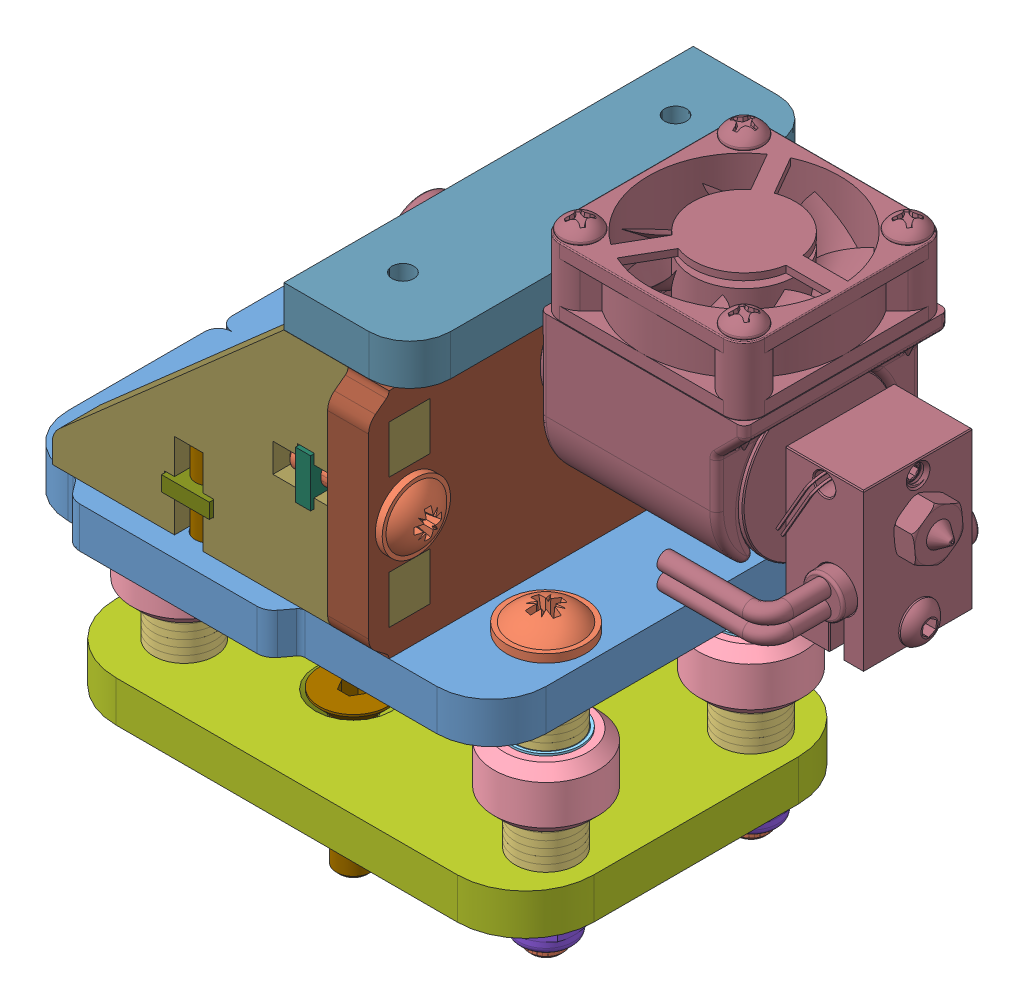
SolidWorks assembly carriage_axis_x, configuration По умолчанию. Lengths in mm.
Overall size (118.69 102.68 87.12).
97 component instances, 16 part files, 168 mates.
Components (placement in the parent):
- carriage_axis_x_plywood-3: carriage_axis_x_plywood [По умолчанию] at origin size (101.86 6 70.03)
- DIN967-1: DIN967 [М5х40] at (-25 9.55 -15) x (0 -1 0) z (0 0 1) size (43.47 34 34.42)
- DIN967-2: DIN967 [М5х40] at (-25 9.55 15) x (0 -1 0) z (0 0 1) size (43.47 34 34.42)
- DIN967-3: DIN967 [М5х40] at (28 9.55 -15) x (0 -1 0) z (0 0 1) size (43.47 34 34.42)
- DIN967-4: DIN967 [М5х40] at (28 9.55 15) x (0 -1 0) z (0.973575 0 0.228367) size (43.47 34 34.42)
- din433_m5-1: din433_m5 [По умолчанию] at (28 0 15) x (1 0 0) z (0 -1 0) size (9 9 1)
- din433_m5-2: din433_m5 [По умолчанию] at (28 -2 15) x (-0.882011 0 -0.471229) z (0 1 0) size (9 9 1)
- din433_m5-3: din433_m5 [По умолчанию] at (28 -3 15) x (-0.882011 0 -0.471229) z (0 1 0) size (9 9 1)
- din433_m5-4: din433_m5 [По умолчанию] at (28 -4 15) x (-0.882011 0 -0.471229) z (0 1 0) size (9 9 1)
- din433_m5-5: din433_m5 [По умолчанию] at (28 -5 15) x (-0.986157 0 -0.165812) z (0 1 0) size (9 9 1)
- din433_m5-6: din433_m5 [По умолчанию] at (28 -3 -15) x (-0.882011 0 -0.471229) z (0 1 0) size (9 9 1)
- din433_m5-7: din433_m5 [По умолчанию] at (28 -2 -15) x (-0.882011 0 -0.471229) z (0 1 0) size (9 9 1)
- din433_m5-8: din433_m5 [По умолчанию] at (28 -1 -15) x (-0.706556 0 -0.707657) z (0 1 0) size (9 9 1)
- din433_m5-9: din433_m5 [По умолчанию] at (28 -4 -15) x (-0.882011 0 -0.471229) z (0 1 0) size (9 9 1)
- din433_m5-10: din433_m5 [По умолчанию] at (28 -5 -15) x (0.996128 0 0.087912) z (0 -1 0) size (9 9 1)
- din433_m5-11: din433_m5 [По умолчанию] at (28 -5 -15) x (-0.882011 0 -0.471229) z (0 1 0) size (9 9 1)
- din433_m5-12: din433_m5 [По умолчанию] at (-25 -3 15) x (-0.955012 0 -0.296566) z (0 1 0) size (9 9 1)
- din433_m5-13: din433_m5 [По умолчанию] at (-25 -4 15) x (-0.955012 0 -0.296566) z (0 1 0) size (9 9 1)
- din433_m5-14: din433_m5 [По умолчанию] at (-25 -5 15) x (-0.827257 0 -0.561823) z (0 1 0) size (9 9 1)
- din433_m5-15: din433_m5 [По умолчанию] at (-25 -2 15) x (-0.955012 0 -0.296566) z (0 1 0) size (9 9 1)
- din433_m5-16: din433_m5 [По умолчанию] at (-25 0 15) x (0.982082 0 -0.188455) z (0 -1 0) size (9 9 1)
- din433_m5-17: din433_m5 [По умолчанию] at (-25 -2 -15) x (-0.996489 0 -0.083718) z (0 1 0) size (9 9 1)
- din433_m5-18: din433_m5 [По умолчанию] at (-25 -3 -15) x (-0.996489 0 -0.083718) z (0 1 0) size (9 9 1)
- din433_m5-19: din433_m5 [По умолчанию] at (-25 -4 -15) x (-0.928921 0 -0.370279) z (0 1 0) size (9 9 1)
- din433_m5-20: din433_m5 [По умолчанию] at (-25 -1 -15) x (-0.996489 0 -0.083718) z (0 1 0) size (9 9 1)
- din433_m5-28: din433_m5 [По умолчанию] at (-25 -5 -15) x (0.980186 0 0.198081) z (0 -1 0) size (9 9 1)
- din433_m5-29: din433_m5 [По умолчанию] at (-25 -4 -15) x (0.980186 0 0.198081) z (0 -1 0) size (9 9 1)
- din433_m5-27: din433_m5 [По умолчанию] at (28 -5 15) x (0.91627 0 0.40056) z (0 -1 0) size (9 9 1)
- din433_m5-21: din433_m5 [По умолчанию] at (-25 -6 15) x (-0.552382 0 -0.833591) z (0 1 0) size (9 9 1)
- Delrin Mini V Wheel Kit-1: Delrin Mini V Wheel Kit [По умолчанию] at (-25 -10.7 15) x (0 1 0) z (0 0 1) size (9.4 15.23 15.23)
  - Delrin Mini V Wheel-1: Delrin Mini V Wheel [Default] at origin size (8.8 15.23 15.23)
  - Mini Ball Bearing 105zz 5x10x4-1: Mini Ball Bearing 105zz 5x10x4 [Default] at (2.6 0 0) size (4.2 10 10)
  - Mini Ball Bearing 105zz 5x10x4-2: Mini Ball Bearing 105zz 5x10x4 [Default] at (-2.6 0 0) size (4.2 10 10)
  - Mini V Wheel Precision Shim-2: Mini V Wheel Precision Shim [По умолчанию] at (-0.5 0 0) size (1 8 8)
- din433_m5-30: din433_m5 [По умолчанию] at (-25 -19.4 15) x (0.999952 0 0.009811) z (0 -1 0) size (9 9 1)
- din433_m5-31: din433_m5 [По умолчанию] at (-25 -20.4 15) x (0.999952 0 0.009811) z (0 -1 0) size (9 9 1)
- din433_m5-32: din433_m5 [По умолчанию] at (-25 -16.4 15) x (-0.994411 0 0.105575) z (0 1 0) size (9 9 1)
- din433_m5-33: din433_m5 [По умолчанию] at (-25 -19.4 15) x (-0.982057 0 -0.188585) z (0 1 0) size (9 9 1)
- din433_m5-34: din433_m5 [По умолчанию] at (-25 -18.4 15) x (-0.994411 0 0.105575) z (0 1 0) size (9 9 1)
- din433_m5-35: din433_m5 [По умолчанию] at (-25 -17.4 15) x (-0.994411 0 0.105575) z (0 1 0) size (9 9 1)
- Delrin Mini V Wheel Kit-2: Delrin Mini V Wheel Kit [По умолчанию] at (-25 -10.7 -15) x (0 -1 0) z (0.990454 0 -0.137844) size (9.4 15.23 15.23)
  - Delrin Mini V Wheel-1: Delrin Mini V Wheel [Default] at origin size (8.8 15.23 15.23)
  - Mini Ball Bearing 105zz 5x10x4-1: Mini Ball Bearing 105zz 5x10x4 [Default] at (2.6 0 0) size (4.2 10 10)
  - Mini Ball Bearing 105zz 5x10x4-2: Mini Ball Bearing 105zz 5x10x4 [Default] at (-2.6 0 0) size (4.2 10 10)
  - Mini V Wheel Precision Shim-2: Mini V Wheel Precision Shim [По умолчанию] at (-0.5 0 0) size (1 8 8)
- din433_m5-42: din433_m5 [По умолчанию] at (-25 -20.4 -15) x (0.983884 0 -0.17881) z (0 -1 0) size (9 9 1)
- din433_m5-43: din433_m5 [По умолчанию] at (-25 -16.4 -15) x (-0.956697 0 0.291085) z (0 1 0) size (9 9 1)
- din433_m5-44: din433_m5 [По умолчанию] at (-25 -19.4 -15) x (-1 0 -0.000132) z (0 1 0) size (9 9 1)
- din433_m5-45: din433_m5 [По умолчанию] at (-25 -18.4 -15) x (-0.956697 0 0.291085) z (0 1 0) size (9 9 1)
- din433_m5-46: din433_m5 [По умолчанию] at (-25 -17.4 -15) x (-0.956697 0 0.291085) z (0 1 0) size (9 9 1)
- din433_m5-47: din433_m5 [По умолчанию] at (-25 -19.4 -15) x (0.983884 0 -0.17881) z (0 -1 0) size (9 9 1)
- Delrin Mini V Wheel Kit-3: Delrin Mini V Wheel Kit [По умолчанию] at (28 -10.7 -15) x (0 1 0) z (0 0 1) size (9.4 15.23 15.23)
  - Delrin Mini V Wheel-1: Delrin Mini V Wheel [Default] at origin size (8.8 15.23 15.23)
  - Mini Ball Bearing 105zz 5x10x4-1: Mini Ball Bearing 105zz 5x10x4 [Default] at (2.6 0 0) size (4.2 10 10)
  - Mini Ball Bearing 105zz 5x10x4-2: Mini Ball Bearing 105zz 5x10x4 [Default] at (-2.6 0 0) size (4.2 10 10)
  - Mini V Wheel Precision Shim-2: Mini V Wheel Precision Shim [По умолчанию] at (-0.5 0 0) size (1 8 8)
- Delrin Mini V Wheel Kit-4: Delrin Mini V Wheel Kit [По умолчанию] at (28 -10.7 15) x (0 -1 0) z (-0.546944 0 0.837169) size (9.4 15.23 15.23)
  - Delrin Mini V Wheel-1: Delrin Mini V Wheel [Default] at origin size (8.8 15.23 15.23)
  - Mini Ball Bearing 105zz 5x10x4-1: Mini Ball Bearing 105zz 5x10x4 [Default] at (2.6 0 0) size (4.2 10 10)
  - Mini Ball Bearing 105zz 5x10x4-2: Mini Ball Bearing 105zz 5x10x4 [Default] at (-2.6 0 0) size (4.2 10 10)
  - Mini V Wheel Precision Shim-2: Mini V Wheel Precision Shim [По умолчанию] at (-0.5 0 0) size (1 8 8)
- din433_m5-54: din433_m5 [По умолчанию] at (28 -16.4 15) x (-0.124351 0 0.992238) z (0 1 0) size (9 9 1)
- din433_m5-55: din433_m5 [По умолчанию] at (28 -19.4 15) x (-0.982107 0 0.188325) z (0 1 0) size (9 9 1)
- din433_m5-56: din433_m5 [По умолчанию] at (28 -18.4 15) x (-0.884699 0 0.466164) z (0 1 0) size (9 9 1)
- din433_m5-57: din433_m5 [По умолчанию] at (28 -17.4 15) x (-0.884699 0 0.466164) z (0 1 0) size (9 9 1)
- din433_m5-58: din433_m5 [По умолчанию] at (28 -19.4 15) x (0.932557 0 -0.361024) z (0 -1 0) size (9 9 1)
- din433_m5-59: din433_m5 [По умолчанию] at (28 -20.4 15) x (0.932557 0 -0.361024) z (0 -1 0) size (9 9 1)
- din433_m5-132: din433_m5 [По умолчанию] at (28 -18.4 -15) x (-0.884699 0 0.466164) z (0 1 0) size (9 9 1)
- din433_m5-133: din433_m5 [По умолчанию] at (28 -20.4 -15) x (0.932557 0 -0.361024) z (0 -1 0) size (9 9 1)
- din433_m5-134: din433_m5 [По умолчанию] at (28 -19.4 -15) x (0.932557 0 -0.361024) z (0 -1 0) size (9 9 1)
- din433_m5-135: din433_m5 [По умолчанию] at (28 -17.4 -15) x (-0.884699 0 0.466164) z (0 1 0) size (9 9 1)
- din433_m5-136: din433_m5 [По умолчанию] at (28 -19.4 -15) x (-0.982107 0 0.188325) z (0 1 0) size (9 9 1)
- din433_m5-137: din433_m5 [По умолчанию] at (28 -16.4 -15) x (0.998156 0 0.060708) z (0 1 0) size (9 9 1)
- carriage_axis_x_plywood_bottom-2: carriage_axis_x_plywood_bottom [По умолчанию] at (0 -27.4 0) size (70 6 50)
- DIN 985-1: DIN 985 [Verzle DIN 985 - M5] at (-25 -27.4 -15) x (0 1 0) z (1 0 0) size (5 9.24 8)
- DIN 985-2: DIN 985 [Verzle DIN 985 - M5] at (-25 -27.4 15) x (0 1 0) z (1 0 0) size (5 9.24 8)
- DIN 985-3: DIN 985 [Verzle DIN 985 - M5] at (28 -27.4 -15) x (0 1 0) z (1 0 0) size (5 9.24 8)
- DIN 985-4: DIN 985 [Verzle DIN 985 - M5] at (28 -27.4 15) x (0 1 0) z (1 0 0) size (5 9.24 8)
- DIN 7991-1: DIN 7991 [ISO 7991 M05 x  20] at (-6.1594 -21.1 9.0403) x (0 -1 0) z (0 0 1) size (22.8 40 22.08)
- DIN 7991-2: DIN 7991 [ISO 7991 M05 x  20] at (-6.1594 -21.7 -8.1926) x (0 -1 0) z (0 0 1) size (22.8 40 22.08)
- din433_m5-138: din433_m5 [По умолчанию] at (-6.1594 -28.4 -8.1926) x (-0.996489 0 -0.083718) z (0 1 0) size (9 9 1)
- din433_m5-139: din433_m5 [По умолчанию] at (-6.1594 -28.4 9.0403) x (-0.996489 0 -0.083718) z (0 1 0) size (9 9 1)
- DIN 439-1: DIN 439 [По умолчанию] at (-6.1594 -31.1 -8.1926) size (9.08 2.7 8)
- DIN 439-2: DIN 439 [По умолчанию] at (-6.1594 -31.1 9.0403) size (9.08 2.7 8)
- carriage_x_console-1: carriage_x_console [По умолчанию] at (20 37.0784 4.0204) x (0 0 -1) z (-1 0 0) size (66 34 6)
- carriage_x_console_rectangel-1: carriage_x_console_rectangel [По умолчанию] at (-30.8109 -0.0784 24) x (-1 0 0) z (0 0 -1) size (62 46 6)
- carriage_x_console_rectangel-2: carriage_x_console_rectangel [По умолчанию] at (-30.8109 -0.0784 -30) x (-1 0 0) z (0 0 -1) size (62 46 6)
- Kit Extrusora - Hotend E3D-V6_175-300-1: Kit Extrusora - Hotend E3D-V6_175-300 [По умолчанию] at (72.5 32 0) x (0 0 1) z (0 -1 0) size (34.25 77.7 41.62)
- Деталь4^carriage_axis_x-1: Деталь4^carriage_axis_x [По умолчанию] at (20 40 4.0204) x (0 0 1) z (0 1 0) size (59.93 19.62 6) (virtual)
- DIN967-5: DIN967 [M4х16] at (23.05 23 27) x (-1 0 0) z (0 0 1) size (18.96 34 34.42)
- din 562 m4-1: din 562 m4 [По умолчанию] at (9 23.0002 26.9982) x (0 -1 0) z (-1 0 0) size (7 7 2.2)
- DIN967-6: DIN967 [M4х16] at (23.05 23 -27) x (-1 0 0) z (0 0 -1) size (18.96 34 34.42)
- din 562 m4-2: din 562 m4 [По умолчанию] at (9 22.9998 -26.9982) x (0 1 0) z (-1 0 0) size (7 7 2.2)
- DIN 7991-3: DIN 7991 [ISO 7991 M04 x  16] at (-9.3228 0 -27) x (0 1 0) z (0 0 -1) size (18.3 40 22.08)
- din 562 m4din-1: din 562 m4din [По умолчанию] at (-9.3228 11 -27) x (1 0 0) z (0 1 0) size (7 7 2.2)
- DIN 7991-4: DIN 7991 [ISO 7991 M04 x  16] at (-9.3228 0 27) x (0 1 0) z (0 0 1) size (18.3 40 22.08)
- din 562 m4din-2: din 562 m4din [По умолчанию] at (-9.3228 11 27) x (-1 0 0) z (0 1 0) size (7 7 2.2)
Mates (geometry in assembly coordinates):
- Концентричный11: concentric anti-aligned: cylinder of carriage_axis_x_plywood-3 through (-25 6 -15) axis (0 -1 0) radius 2.55; cylinder of DIN967-1 through (-25 15.9 -15) axis (0 1 0) radius 5.75
- Совпадение11: coincident anti-aligned: plane of carriage_axis_x_plywood-3 through (27 6 -22) normal (0 1 0); plane of DIN967-1 through (-22.5 6 -15) normal (0 -1 0)
- Концентричный21: concentric anti-aligned: cylinder of carriage_axis_x_plywood-3 through (-25 6 15) axis (0 -1 0) radius 2.55; cylinder of DIN967-2 through (-25 15.9 15) axis (0 1 0) radius 5.75
- Совпадение21: coincident anti-aligned: plane of carriage_axis_x_plywood-3 through (27 6 -22) normal (0 1 0); plane of DIN967-2 through (-22.5 6 15) normal (0 -1 0)
- Концентричный31: concentric anti-aligned: cylinder of DIN967-3 through (28 15.9 -15) axis (0 1 0) radius 5.75; circle of carriage_axis_y_plywood_left-1
- Совпадение31: coincident anti-aligned: plane of carriage_axis_x_plywood-3 through (27 6 -22) normal (0 1 0); plane of DIN967-3 through (30.5 6 -15) normal (0 -1 0)
- Совпадение41: coincident anti-aligned: plane of carriage_axis_x_plywood-3 through (27 6 -22) normal (0 1 0); plane of DIN967-4 through (28.5709 6 12.5661) normal (0 -1 0)
- Концентричный5: concentric anti-aligned: cylinder of carriage_axis_x_plywood-3 through (28 6 15) axis (0 -1 0) radius 2.55; cylinder of DIN967-4 through (28 15.9 15) axis (0 1 0) radius 2.5
- Совпадение5: coincident anti-aligned: plane of carriage_axis_x_plywood-3 through (27 0 -22) normal (0 -1 0); plane of din433_m5-1 through (28 0 15) normal (0 1 0)
- Концентричный6: concentric anti-aligned: cylinder of DIN967-4 through (28 15.9 15) axis (0 1 0) radius 2.5; circle of din433_m5-1
- Концентричный7: concentric aligned: cylinder of DIN967-4 through (28 15.9 15) axis (0 1 0) radius 2.5; circle of din433_m5-2
- Совпадение7: coincident anti-aligned: plane of din433_m5-1 through (28 -1 15) normal (0 -1 0); plane of din433_m5-2 through (28 -1 15) normal (0 1 0)
- Совпадение10: coincident anti-aligned: plane of din433_m5-3 through (28 -3 15) normal (0 -1 0); plane of din433_m5-4 through (28 -3 15) normal (0 1 0)
- Совпадение11: coincident aligned: circle of din433_m5-3; circle of din433_m5-4
- Совпадение12: coincident anti-aligned: plane of din433_m5-4 through (28 -4 15) normal (0 -1 0); plane of din433_m5-5 through (28 -4 15) normal (0 1 0)
- Совпадение13: coincident aligned: circle of din433_m5-4; circle of din433_m5-5
- Совпадение14: coincident anti-aligned: plane of din433_m5-2 through (28 -2 15) normal (0 -1 0); plane of din433_m5-3 through (28 -2 15) normal (0 1 0)
- Совпадение15: coincident aligned: circle of din433_m5-2; circle of din433_m5-3
- Совпадение16: coincident anti-aligned: plane of carriage_axis_x_plywood-3 through (27 0 -22) normal (0 -1 0); plane of din433_m5-8 through (28 0 -15) normal (0 1 0)
- Концентричный8: concentric aligned: cylinder of DIN967-3 through (28 15.9 -15) axis (0 1 0) radius 2.5; circle of din433_m5-8
- Совпадение17: coincident anti-aligned: plane of din433_m5-7 through (28 -1 -15) normal (0 1 0); plane of din433_m5-8 through (28 -1 -15) normal (0 -1 0)
- Совпадение18: coincident aligned: circle of din433_m5-7; circle of din433_m5-8
- Совпадение19: coincident anti-aligned: plane of din433_m5-6 through (28 -2 -15) normal (0 1 0); plane of din433_m5-7 through (28 -2 -15) normal (0 -1 0)
- Концентричный9: concentric aligned: cylinder of DIN967-3 through (28 15.9 -15) axis (0 1 0) radius 2.5; circle of din433_m5-6
- Совпадение20: coincident anti-aligned: plane of din433_m5-6 through (28 -3 -15) normal (0 -1 0); plane of din433_m5-9 through (28 -3 -15) normal (0 1 0)
- Концентричный10: concentric aligned: cylinder of DIN967-3 through (28 15.9 -15) axis (0 1 0) radius 2.5; circle of din433_m5-9
- Совпадение22: coincident anti-aligned: plane of din433_m5-9 through (28 -4 -15) normal (0 -1 0); plane of din433_m5-11 through (28 -4 -15) normal (0 1 0)
- Концентричный11: concentric aligned: cylinder of DIN967-3 through (28 15.9 -15) axis (0 1 0) radius 2.5; circle of din433_m5-11
- Совпадение23: coincident anti-aligned: plane of din433_m5-10 through (28 -5 -15) normal (0 1 0); plane of din433_m5-11 through (28 -5 -15) normal (0 -1 0)
- Концентричный13: concentric anti-aligned: cylinder of DIN967-3 through (28 15.9 -15) axis (0 1 0) radius 2.5; circle of din433_m5-10
- Совпадение24: coincident anti-aligned: plane of din433_m5-15 through (-25 -1 15) normal (0 1 0); plane of din433_m5-16 through (-25 -1 15) normal (0 -1 0)
- Совпадение25: coincident anti-aligned: plane of din433_m5-12 through (-25 -3 15) normal (0 -1 0); plane of din433_m5-13 through (-25 -3 15) normal (0 1 0)
- Совпадение26: coincident aligned: circle of din433_m5-12; circle of din433_m5-13
- Совпадение27: coincident anti-aligned: plane of din433_m5-13 through (-25 -4 15) normal (0 -1 0); plane of din433_m5-14 through (-25 -4 15) normal (0 1 0)
- Совпадение28: coincident aligned: circle of din433_m5-13; circle of din433_m5-14
- Совпадение29: coincident anti-aligned: plane of din433_m5-12 through (-25 -2 15) normal (0 1 0); plane of din433_m5-15 through (-25 -2 15) normal (0 -1 0)
- Совпадение30: coincident aligned: circle of din433_m5-12; circle of din433_m5-15
- Совпадение33: coincident anti-aligned: plane of din433_m5-17 through (-25 -2 -15) normal (0 -1 0); plane of din433_m5-18 through (-25 -2 -15) normal (0 1 0)
- Совпадение34: coincident aligned: circle of din433_m5-17; circle of din433_m5-18
- Совпадение35: coincident anti-aligned: plane of din433_m5-18 through (-25 -3 -15) normal (0 -1 0); plane of din433_m5-19 through (-25 -3 -15) normal (0 1 0)
- Совпадение36: coincident aligned: circle of din433_m5-18; circle of din433_m5-19
- Совпадение37: coincident anti-aligned: plane of din433_m5-17 through (-25 -1 -15) normal (0 1 0); plane of din433_m5-20 through (-25 -1 -15) normal (0 -1 0)
- Совпадение38: coincident aligned: circle of din433_m5-17; circle of din433_m5-20
- Концентричный15: concentric aligned: cylinder of DIN967-2 through (-25 15.9 15) axis (0 1 0) radius 2.5; circle of din433_m5-14
- Концентричный16: concentric anti-aligned: cylinder of DIN967-2 through (-25 15.9 15) axis (0 1 0) radius 2.5; circle of din433_m5-16
- Совпадение54: coincident anti-aligned: plane of din433_m5-14 through (-25 -5 15) normal (0 -1 0); plane of din433_m5-21 through (-25 -5 15) normal (0 1 0)
- Концентричный17: concentric aligned: cylinder of DIN967-2 through (-25 15.9 15) axis (0 1 0) radius 2.5; circle of din433_m5-21
- Совпадение55: coincident anti-aligned: plane of din433_m5-5 through (28 -5 15) normal (0 -1 0); plane of din433_m5-27 through (28 -5 15) normal (0 1 0)
- Концентричный18: concentric anti-aligned: cylinder of DIN967-4 through (28 15.9 15) axis (0 1 0) radius 2.5; circle of din433_m5-27
- Концентричный19: concentric aligned: cylinder of DIN967-1 through (-25 15.9 -15) axis (0 1 0) radius 2.5; circle of din433_m5-20
- Совпадение56: coincident anti-aligned: plane of din433_m5-19 through (-25 -4 -15) normal (0 -1 0); plane of din433_m5-29 through (-25 -4 -15) normal (0 1 0)
- Концентричный20: concentric anti-aligned: cylinder of DIN967-1 through (-25 15.9 -15) axis (0 1 0) radius 2.5; circle of din433_m5-29
- Совпадение57: coincident anti-aligned: plane of din433_m5-28 through (-25 -5 -15) normal (0 1 0); plane of din433_m5-29 through (-25 -5 -15) normal (0 -1 0)
- Концентричный21: concentric anti-aligned: cylinder of DIN967-1 through (-25 15.9 -15) axis (0 1 0) radius 2.5; circle of din433_m5-28
- Совпадение58: coincident anti-aligned: plane of carriage_axis_x_plywood-3 through (27 0 -22) normal (0 -1 0); plane of din433_m5-20 through (-25 0 -15) normal (0 1 0)
- Совпадение59: coincident anti-aligned: plane of din433_m5-21 through (-25 -6 15) normal (0 -1 0); plane of Delrin Mini V Wheel Kit-1/Mini Ball Bearing 105zz 5x10x4-1 through (-27.5 -6 15) normal (0 1 0)
- Совпадение60: coincident aligned: cylinder of DIN967-2 through (-25 15.9 15) axis (0 1 0) radius 2.5; circle of Delrin Mini V Wheel Kit-1/Mini Ball Bearing 105zz 5x10x4-2
- Совпадение61: coincident anti-aligned: plane of din433_m5-34 through (-25 -17.4 15) normal (0 1 0); plane of din433_m5-35 through (-25 -17.4 15) normal (0 -1 0)
- Совпадение62: coincident aligned: circle of din433_m5-34; circle of din433_m5-35
- Совпадение63: coincident anti-aligned: plane of din433_m5-33 through (-25 -18.4 15) normal (0 1 0); plane of din433_m5-34 through (-25 -18.4 15) normal (0 -1 0)
- Совпадение64: coincident aligned: circle of din433_m5-33; circle of din433_m5-34
- Совпадение65: coincident anti-aligned: plane of din433_m5-32 through (-25 -16.4 15) normal (0 -1 0); plane of din433_m5-35 through (-25 -16.4 15) normal (0 1 0)
- Совпадение67: coincident anti-aligned: plane of din433_m5-30 through (-25 -19.4 15) normal (0 1 0); plane of din433_m5-33 through (-25 -19.4 15) normal (0 -1 0)
- Совпадение68: coincident anti-aligned: plane of din433_m5-30 through (-25 -20.4 15) normal (0 -1 0); plane of din433_m5-31 through (-25 -20.4 15) normal (0 1 0)
- Совпадение80: coincident anti-aligned: plane of Delrin Mini V Wheel Kit-1/Mini Ball Bearing 105zz 5x10x4-2 through (-27.5 -15.4 15) normal (0 -1 0); plane of din433_m5-32 through (-25 -15.4 15) normal (0 1 0)
- Концентричный22: concentric aligned: cylinder of DIN967-2 through (-25 15.9 15) axis (0 1 0) radius 2.5; circle of din433_m5-32
- Концентричный23: concentric aligned: cylinder of DIN967-2 through (-25 15.9 15) axis (0 1 0) radius 2.5; circle of din433_m5-35
- Концентричный24: concentric anti-aligned: cylinder of DIN967-2 through (-25 15.9 15) axis (0 1 0) radius 2.5; circle of din433_m5-30
- Концентричный25: concentric aligned: cylinder of DIN967-2 through (-25 15.9 15) axis (0 1 0) radius 2.5; cylinder of din433_m5-31 through (-25 -21.4 15) axis (0 1 0) radius 4.5
- Совпадение81: coincident anti-aligned: plane of din433_m5-28 through (-25 -6 -15) normal (0 -1 0); plane of Delrin Mini V Wheel Kit-2/Mini Ball Bearing 105zz 5x10x4-2 through (-25.3446 -6 -17.4761) normal (0 1 0)
- Совпадение82: coincident anti-aligned: cylinder of DIN967-1 through (-25 15.9 -15) axis (0 1 0) radius 2.5; circle of Delrin Mini V Wheel Kit-2/Mini Ball Bearing 105zz 5x10x4-1
- Совпадение83: coincident anti-aligned: plane of din433_m5-45 through (-25 -17.4 -15) normal (0 1 0); plane of din433_m5-46 through (-25 -17.4 -15) normal (0 -1 0)
- Совпадение84: coincident aligned: circle of din433_m5-45; circle of din433_m5-46
- Совпадение85: coincident anti-aligned: plane of din433_m5-44 through (-25 -18.4 -15) normal (0 1 0); plane of din433_m5-45 through (-25 -18.4 -15) normal (0 -1 0)
- Совпадение86: coincident aligned: circle of din433_m5-44; circle of din433_m5-45
- Совпадение87: coincident anti-aligned: plane of din433_m5-43 through (-25 -16.4 -15) normal (0 -1 0); plane of din433_m5-46 through (-25 -16.4 -15) normal (0 1 0)
- Совпадение88: coincident anti-aligned: plane of din433_m5-44 through (-25 -19.4 -15) normal (0 -1 0); plane of din433_m5-47 through (-25 -19.4 -15) normal (0 1 0)
- Совпадение89: coincident anti-aligned: plane of din433_m5-42 through (-25 -20.4 -15) normal (0 1 0); plane of din433_m5-47 through (-25 -20.4 -15) normal (0 -1 0)
- Совпадение99: coincident anti-aligned: plane of carriage_axis_x_plywood-3 through (27 0 -22) normal (0 -1 0); plane of din433_m5-16 through (-25 0 15) normal (0 1 0)
- Совпадение100: coincident anti-aligned: plane of Delrin Mini V Wheel Kit-2/Mini Ball Bearing 105zz 5x10x4-1 through (-25.3446 -15.4 -17.4761) normal (0 -1 0); plane of din433_m5-43 through (-25 -15.4 -15) normal (0 1 0)
- Концентричный26: concentric anti-aligned: circle of din433_m5-42; circle of din433_m5-43
- Концентричный27: concentric anti-aligned: circle of din433_m5-43; circle of din433_m5-47
- Концентричный28: concentric anti-aligned: circle of din433_m5-42; circle of din433_m5-44
- Концентричный29: concentric aligned: circle of Delrin Mini V Wheel Kit-2/Mini Ball Bearing 105zz 5x10x4-1; cylinder of din433_m5-43 through (-25 -15.4 -15) axis (0 -1 0) radius 4.5
- Совпадение104: coincident anti-aligned: plane of din433_m5-10 through (28 -6 -15) normal (0 -1 0); plane of Delrin Mini V Wheel Kit-3/Mini Ball Bearing 105zz 5x10x4-1 through (25.5 -6 -15) normal (0 1 0)
- Совпадение105: coincident aligned: cylinder of DIN967-3 through (28 15.9 -15) axis (0 1 0) radius 2.5; circle of Delrin Mini V Wheel Kit-3/Mini Ball Bearing 105zz 5x10x4-2
- Совпадение106: coincident anti-aligned: plane of din433_m5-27 through (28 -6 15) normal (0 -1 0); plane of Delrin Mini V Wheel Kit-4/Mini Ball Bearing 105zz 5x10x4-2 through (30.0929 -6 16.3674) normal (0 1 0)
- Концентричный30: concentric anti-aligned: cylinder of DIN967-4 through (28 15.9 15) axis (0 1 0) radius 2.5; cylinder of Delrin Mini V Wheel Kit-4/Mini Ball Bearing 105zz 5x10x4-1 through (28 -13.3 15) axis (0 -1 0) radius 2.5
- Совпадение107: coincident anti-aligned: plane of din433_m5-56 through (28 -17.4 15) normal (0 1 0); plane of din433_m5-57 through (28 -17.4 15) normal (0 -1 0)
- Совпадение108: coincident aligned: circle of din433_m5-56; circle of din433_m5-57
- Совпадение109: coincident anti-aligned: plane of din433_m5-55 through (28 -18.4 15) normal (0 1 0); plane of din433_m5-56 through (28 -18.4 15) normal (0 -1 0)
- Совпадение110: coincident aligned: circle of din433_m5-55; circle of din433_m5-56
- Совпадение111: coincident anti-aligned: plane of din433_m5-54 through (28 -16.4 15) normal (0 -1 0); plane of din433_m5-57 through (28 -16.4 15) normal (0 1 0)
- Совпадение112: coincident anti-aligned: plane of din433_m5-55 through (28 -19.4 15) normal (0 -1 0); plane of din433_m5-58 through (28 -19.4 15) normal (0 1 0)
- Совпадение113: coincident anti-aligned: plane of din433_m5-58 through (28 -20.4 15) normal (0 -1 0); plane of din433_m5-59 through (28 -20.4 15) normal (0 1 0)
- Концентричный31: concentric anti-aligned: circle of din433_m5-54; circle of din433_m5-59
- Концентричный32: concentric anti-aligned: circle of din433_m5-54; circle of din433_m5-58
- Концентричный33: concentric anti-aligned: circle of din433_m5-55; circle of din433_m5-59
- Концентричный83: concentric anti-aligned: circle of din433_m5-133; circle of din433_m5-136
- Совпадение200: coincident anti-aligned: plane of din433_m5-132 through (28 -18.4 -15) normal (0 -1 0); plane of din433_m5-136 through (28 -18.4 -15) normal (0 1 0)
- Совпадение201: coincident aligned: circle of din433_m5-132; circle of din433_m5-135
- Совпадение202: coincident anti-aligned: plane of din433_m5-132 through (28 -17.4 -15) normal (0 1 0); plane of din433_m5-135 through (28 -17.4 -15) normal (0 -1 0)
- Концентричный84: concentric anti-aligned: circle of din433_m5-134; circle of din433_m5-137
- Совпадение203: coincident anti-aligned: plane of din433_m5-135 through (28 -16.4 -15) normal (0 1 0); plane of din433_m5-137 through (28 -16.4 -15) normal (0 -1 0)
- Концентричный85: concentric anti-aligned: circle of din433_m5-133; circle of din433_m5-137
- Совпадение204: coincident anti-aligned: plane of din433_m5-134 through (28 -19.4 -15) normal (0 1 0); plane of din433_m5-136 through (28 -19.4 -15) normal (0 -1 0)
- Совпадение205: coincident aligned: circle of din433_m5-132; circle of din433_m5-136
- Совпадение206: coincident anti-aligned: plane of din433_m5-133 through (28 -20.4 -15) normal (0 1 0); plane of din433_m5-134 through (28 -20.4 -15) normal (0 -1 0)
- Совпадение207: coincident anti-aligned: plane of Delrin Mini V Wheel Kit-3/Mini Ball Bearing 105zz 5x10x4-2 through (25.5 -15.4 -15) normal (0 -1 0); plane of din433_m5-137 through (28 -15.4 -15) normal (0 1 0)
- Концентричный86: concentric aligned: cylinder of DIN967-3 through (28 15.9 -15) axis (0 1 0) radius 2.5; circle of din433_m5-137
- Совпадение208: coincident anti-aligned: plane of Delrin Mini V Wheel Kit-4/Mini Ball Bearing 105zz 5x10x4-1 through (30.0929 -15.4 16.3674) normal (0 -1 0); plane of din433_m5-54 through (28 -15.4 15) normal (0 1 0)
- Концентричный87: concentric aligned: cylinder of DIN967-4 through (28 15.9 15) axis (0 1 0) radius 2.5; circle of din433_m5-54
- Концентричный88: concentric anti-aligned: cylinder of DIN967-1 through (-25 15.9 -15) axis (0 1 0) radius 2.5; circle of carriage_axis_y_plywood_left-2
- Концентричный89: concentric anti-aligned: cylinder of DIN967-2 through (-25 15.9 15) axis (0 1 0) radius 2.5; circle of carriage_axis_y_plywood_left-2
- Совпадение210: coincident anti-aligned: plane of din433_m5-42 through (-25 -21.4 -15) normal (0 -1 0); plane of carriage_axis_x_plywood_bottom-2 through (25 -21.4 -15) normal (0 1 0)
- Совпадение211: coincident anti-aligned: plane of carriage_axis_x_plywood_bottom-2 through (25 -27.4 -15) normal (0 -1 0); plane of DIN 985-1 through (-25 -27.4 -15) normal (0 1 0)
- Концентричный90: concentric anti-aligned: cylinder of DIN967-1 through (-25 15.9 -15) axis (0 1 0) radius 2.5; cylinder of DIN 985-1 through (-25 -35.522 -15) axis (0 -1 0) radius 2.5
- Совпадение212: coincident anti-aligned: plane of carriage_axis_x_plywood_bottom-2 through (25 -27.4 -15) normal (0 -1 0); plane of DIN 985-2 through (-25 -27.4 15) normal (0 1 0)
- Совпадение213: coincident anti-aligned: plane of carriage_axis_x_plywood_bottom-2 through (25 -27.4 -15) normal (0 -1 0); plane of DIN 985-4 through (28 -27.4 15) normal (0 1 0)
- Совпадение214: coincident anti-aligned: plane of carriage_axis_x_plywood_bottom-2 through (25 -27.4 -15) normal (0 -1 0); plane of DIN 985-3 through (28 -27.4 -15) normal (0 1 0)
- Концентричный91: concentric anti-aligned: cylinder of DIN967-2 through (-25 15.9 15) axis (0 1 0) radius 2.5; cylinder of DIN 985-2 through (-25 -35.522 15) axis (0 -1 0) radius 2.5
- Концентричный92: concentric anti-aligned: cylinder of DIN967-3 through (28 15.9 -15) axis (0 1 0) radius 2.5; cylinder of DIN 985-3 through (28 -35.522 -15) axis (0 -1 0) radius 2.5
- Концентричный93: concentric anti-aligned: cylinder of DIN967-4 through (28 15.9 15) axis (0 1 0) radius 2.5; cylinder of DIN 985-4 through (28 -35.522 15) axis (0 -1 0) radius 2.5
- Концентричный94: concentric aligned: cone of carriage_axis_x_plywood_bottom-2 through (-6.1594 -21.4 9.0403) axis (0 -1 0); cone of DIN 7991-1 through (-6.1594 -21.4 9.0403) axis (0 -1 0)
- Совпадение2151: coincident aligned: cone of carriage_axis_x_plywood_bottom-2 through (-6.1594 -21.4 -8.1926) axis (0 -1 0); cone of DIN 7991-2 through (-6.1594 -22 -8.1926) axis (0 -1 0)
- Концентричный95: concentric aligned: cylinder of DIN 7991-2 through (-6.1594 -21.7 -8.1926) axis (0 1 0) radius 2.5; circle of din433_m5-138
- Совпадение216: coincident anti-aligned: plane of carriage_axis_x_plywood_bottom-2 through (25 -27.4 -15) normal (0 -1 0); plane of din433_m5-138 through (-6.1594 -27.4 -8.1926) normal (0 1 0)
- Концентричный97: concentric aligned: cylinder of DIN 7991-1 through (-6.1594 -21.1 9.0403) axis (0 1 0) radius 2.5; circle of din433_m5-139
- Совпадение217: coincident anti-aligned: plane of carriage_axis_x_plywood_bottom-2 through (25 -27.4 -15) normal (0 -1 0); plane of din433_m5-139 through (-6.1594 -27.4 9.0403) normal (0 1 0)
- Концентричный101: concentric aligned: cylinder of DIN 7991-2 through (-6.1594 -21.7 -8.1926) axis (0 1 0) radius 2.5; circle of DIN 439-1
- Концентричный102: concentric aligned: cylinder of DIN 7991-2 through (-6.1594 -21.7 -8.1926) axis (0 1 0) radius 2.5; circle of DIN 439-1
- Совпадение220: coincident anti-aligned: plane of din433_m5-138 through (-6.1594 -28.4 -8.1926) normal (0 -1 0); plane of DIN 439-1 through (-6.1594 -28.4 -8.1926) normal (0 1 0)
- Концентричный103: concentric aligned: cylinder of DIN 7991-1 through (-6.1594 -21.1 9.0403) axis (0 1 0) radius 2.5; circle of DIN 439-2
- Совпадение221: coincident anti-aligned: plane of din433_m5-139 through (-6.1594 -28.4 9.0403) normal (0 -1 0); plane of DIN 439-2 through (-6.1594 -28.4 9.0403) normal (0 1 0)
- Совпадение2152: coincident: point of carriage_axis_x_plywood-3; plane of carriage_x_console-1 through (20 37.0784 0) normal (0 0 -1)
- Совпадение2153: coincident anti-aligned: plane of carriage_axis_x_plywood-3 through (27 6 -22) normal (0 1 0); plane of carriage_x_console-1 through (14 6 30) normal (0 -1 0)
- Совпадение2154: coincident anti-aligned: plane of carriage_x_console-1 through (14 37.0784 4.0204) normal (-1 0 0); plane of carriage_x_console_rectangel-1 through (14 6 30) normal (1 0 0)
- Совпадение2155: coincident aligned: plane of carriage_x_console_rectangel-1 through (-26.3228 8.7909 30) normal (0 0 1); plane of carriage_axis_x_plywood-3 through (-27 6 30) normal (0 0 1)
- Совпадение2156: coincident anti-aligned: plane of carriage_axis_x_plywood-3 through (27 6 -22) normal (0 1 0); plane of carriage_x_console_rectangel-1 through (-27 6 30) normal (0 -1 0)
- Совпадение2157: coincident anti-aligned: plane of carriage_x_console-1 through (14 37.0784 4.0204) normal (-1 0 0); plane of carriage_x_console_rectangel-2 through (14 6 -24) normal (1 0 0)
- Совпадение2158: coincident aligned: plane of carriage_x_console_rectangel-2 through (-26.3228 8.7909 -30) normal (0 0 -1); plane of carriage_axis_x_plywood-3 through (-27 6 -30) normal (0 0 -1)
- Совпадение2159: coincident anti-aligned: plane of carriage_axis_x_plywood-3 through (27 6 -22) normal (0 1 0); plane of carriage_x_console_rectangel-2 through (-27 6 -24) normal (0 -1 0)
- Расстояние1: distance = 15 mm aligned: plane of carriage_x_console-1 through (20 37.0784 4.0204) normal (1 0 0); plane of carriage_axis_x_plywood-3 through (35 6 22) normal (1 0 0)
- Совпадение2161: coincident anti-aligned: plane of carriage_x_console-1 through (14 37.0784 4.0204) normal (-1 0 0); plane of Kit Extrusora - Hotend E3D-V6_175-300-1 through (14 28.497 4.8712) normal (1 0 0)
- Концентричный105: concentric anti-aligned: cylinder of carriage_x_console-1 through (20 32 0) axis (-1 0 0) radius 6.05; cylinder of Kit Extrusora - Hotend E3D-V6_175-300-1 through (17 32 0) axis (1 0 0) radius 6
- Параллельность1: parallel aligned: plane of carriage_x_console-1 through (14 40 30) normal (0 1 0); plane of Kit Extrusora - Hotend E3D-V6_175-300-1 through (54 56.25 12) normal (0 1 0)
- На месте1: in place: plane of carriage_x_console-1 through (14 26 30) normal (0 1 0); plane of ? through (0 26 0) normal (0 1 0); moOrthogonalPlaneRef_w of carriage_x_console-1 through (14 26 30) normal (0 1 0); plane of ? through (0 26 0) normal (0 0 -1); plane of carriage_x_console-1 through (14 26 30) normal (0 1 0); plane of ? through (0 26 0) normal (1 0 0); plane of carriage_x_console-1 through (14 40 30) normal (0 1 0); unknown of Деталь4^carriage_axis_x-1
- Совпадение2163: coincident aligned: plane of carriage_x_console-1; plane of Деталь4^carriage_axis_x-1
- Совпадение2164: coincident aligned: moOrthogonalPlaneRef_w of carriage_x_console-1 through (20 40 4.0204) normal (1 0 0); plane of Деталь4^carriage_axis_x-1 through (20 40 4.0204) normal (1 0 0)
- Совпадение2165: coincident anti-aligned: moOrthogonalPlaneRef_w of carriage_x_console-1 through (20 40 4.0204) normal (0 0 -1); plane of Деталь4^carriage_axis_x-1 through (20 40 4.0204) normal (0 0 1)
- Совпадение21621: coincident anti-aligned: plane of carriage_x_console-1 through (20 37.0784 4.0204) normal (1 0 0); plane of DIN967-5 through (20 21 27) normal (-1 0 0)
- Совпадение2163: coincident anti-aligned: plane of carriage_x_console_rectangel-1 through (-26.3228 8.7909 30) normal (0 0 1); plane of DIN967-5 through (23.05 23 30) normal (0 0 -1)
- Совпадение2164: coincident aligned: plane of carriage_axis_x_plywood-3 through (27 6 -22) normal (0 1 0); plane of DIN967-5 through (23.05 6 27) normal (0 1 0)
- Концентричный107: concentric anti-aligned: cylinder of DIN967-5 through (29.4 23 27) axis (1 0 0) radius 2; cylinder of din 562 m4-1 through (9 23 27) axis (-1 0 0) radius 2
- Совпадение2165: coincident anti-aligned: plane of din 562 m4-1 through (9 23.0002 26.9982) normal (1 0 0); plane of carriage_x_console_rectangel-1 through (9 25.1 24) normal (-1 0 0)
- Совпадение21661: coincident anti-aligned: plane of carriage_x_console-1 through (20 37.0784 4.0204) normal (1 0 0); plane of DIN967-6 through (20 25 -27) normal (-1 0 0)
- Совпадение2167: coincident anti-aligned: plane of carriage_x_console_rectangel-2 through (-26.3228 8.7909 -30) normal (0 0 -1); plane of DIN967-6 through (23.05 23 -30) normal (0 0 1)
- Совпадение2168: coincident aligned: plane of carriage_axis_x_plywood-3 through (27 6 -22) normal (0 1 0); plane of DIN967-6 through (23.05 6 -27) normal (0 1 0)
- Концентричный109: concentric anti-aligned: cylinder of DIN967-6 through (29.4 23 -27) axis (1 0 0) radius 2; cylinder of din 562 m4-2 through (9 23 -27) axis (-1 0 0) radius 2
- Совпадение2169: coincident aligned: plane of carriage_axis_x_plywood-3 through (27 0 -22) normal (0 -1 0); plane of DIN 7991-3 through (-9.3228 0 -27) normal (0 -1 0)
- Совпадение2170: coincident anti-aligned: plane of carriage_axis_x_plywood-3 through (-27 6 -30) normal (0 0 -1); plane of DIN 7991-3 through (-9.3228 0 -30) normal (0 0 1)
- Совпадение2171: coincident anti-aligned: plane of carriage_x_console_rectangel-2 through (-29.3228 8.7909 -24) normal (-1 0 0); plane of DIN 7991-3 through (-29.3228 0 -27) normal (1 0 0)
- Совпадение2173: coincident: point of din 562 m4din-1; line of DIN 7991-3 through (-9.3228 18.3 -27) axis (0 -1 0)
- Совпадение2174: coincident anti-aligned: plane of din 562 m4din-1 through (-9.3228 11 -27) normal (0 -1 0); plane of carriage_x_console_rectangel-2 through (-11.4228 11 -24) normal (0 1 0)
- Совпадение21662: coincident aligned: plane of carriage_axis_x_plywood-3 through (27 0 -22) normal (0 -1 0); plane of DIN 7991-4 through (-9.3228 0 27) normal (0 -1 0)
- Совпадение21663: coincident anti-aligned: plane of carriage_axis_x_plywood-3 through (-27 6 30) normal (0 0 1); plane of DIN 7991-4 through (-9.3228 0 30) normal (0 0 -1)
- Совпадение21664: coincident aligned: plane of carriage_x_console_rectangel-1 through (-29.3228 8.7909 30) normal (-1 0 0); plane of DIN 7991-4 through (-29.3228 0 27) normal (-1 0 0)
- Совпадение21668: coincident: point of din 562 m4din-2; line of DIN 7991-4 through (-9.3228 18.3 27) axis (0 -1 0)
